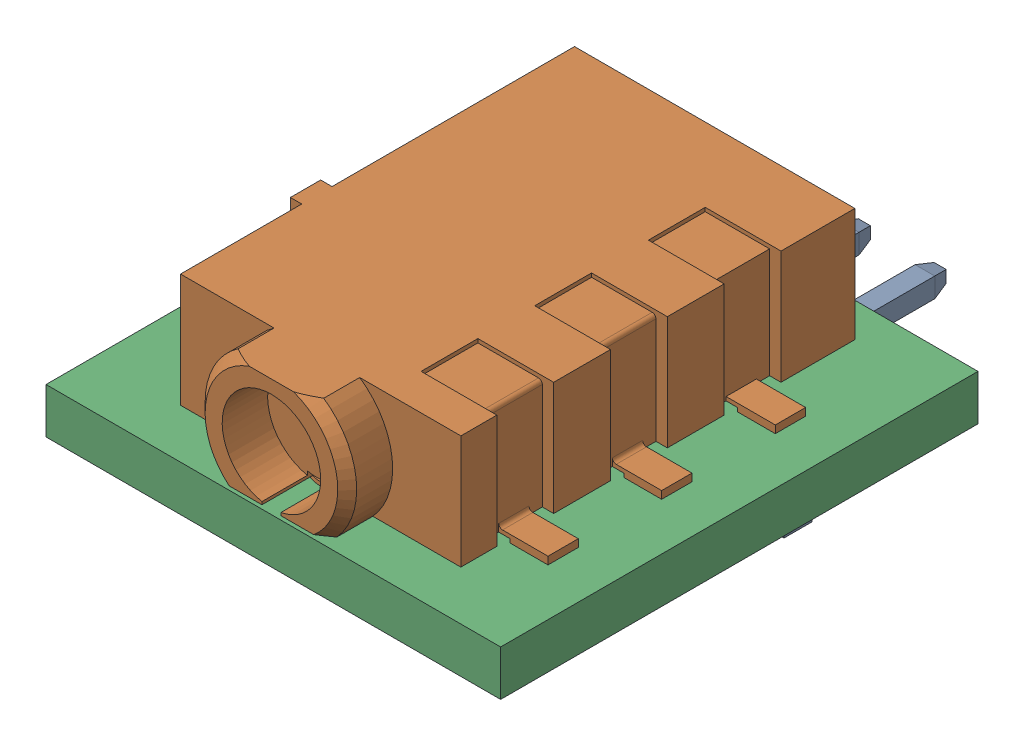
SolidWorks assembly TH2, configuration ﾃﾞﾌｫﾙﾄ. Lengths in mm.
Overall size (12 8.35 16.6).
4 component instances, 3 part files, 0 mates.
Components (placement in the parent):
- 10112690-G03-02ULFc-1: 10112690-G03-02ULFc [ﾃﾞﾌｫﾙﾄ] at (52.8001 34.9499 0.75) x (0 1 0) z (0 0 -1) size (4.05 4 11.75)
- CUI_SJ1-2535-SMT-1: CUI_SJ1-2535-SMT [ﾃﾞﾌｫﾙﾄ] at (50.7501 41.6501 11.4) x (-1 0 0) z (0 0 -1) size (9.4 3.5 11.6)
- 689264912-1: 689264912 [ﾃﾞﾌｫﾙﾄ] at (50.8 39.6 0) size (12 1.2 12.6)
  - Extruded_35-1: Extruded_35 [ﾃﾞﾌｫﾙﾄ] at origin size (12 1.2 12.6)
